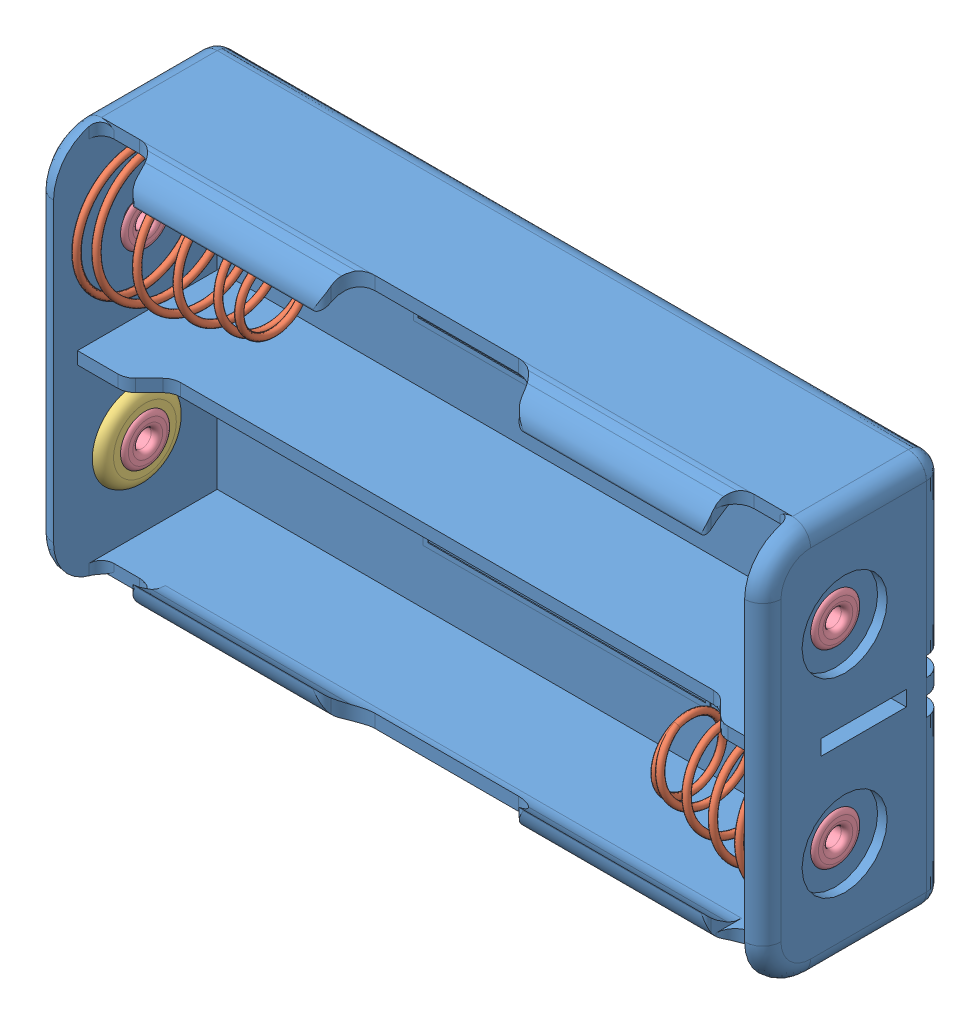
SolidWorks assembly BATTERY HOLDER x2.stp, configuration Default. Lengths in mm.
Overall size (76 41.11 19.41).
9 component instances, 4 part files, 0 mates.
Components (placement in the parent):
- Porta baterias 2x18650.stp-1: Porta baterias 2x18650.stp [Default] at origin size (76 41.11 19)
- Contacto_Helice_v2.0.stp-1: Contacto_Helice_v2.0.stp [Default] at (-35.75 9.925 10.45) x (0 0 -1) z (1 0 0) size (13.74 13.7 14.7)
- Contacto_Helice_v2.0.stp-2: Contacto_Helice_v2.0.stp [Default] at (35.75 -9.925 10.45) x (0 0.924225 0.381849) z (-1 0 0) size (13.74 13.7 14.7)
- Contacto_plano_v1.0.stp-1: Contacto_plano_v1.0.stp [Default] at (36.1 9.925 10.45) x (0 -0.843458 0.537195) z (-1 0 0) size (9 9 1)
- Contacto_plano_v1.0.stp-2: Contacto_plano_v1.0.stp [Default] at (-36.1 -9.925 10.45) x (0 -0.818563 0.574417) z (1 0 0) size (9 9 1)
- remache_v1.0.stp-1: remache_v1.0.stp [Default] at (36.05 9.925 10.45) x (-1 0 0) z (0 -0.633912 0.773406) size (2.5 5.1 5.1)
- remache_v1.0.stp-2: remache_v1.0.stp [Default] at (-36.05 -9.925 10.45) x (-1 0 0) z (0 -0.633912 0.773406) size (2.5 5.1 5.1)
- remache_v1.0.stp-3: remache_v1.0.stp [Default] at (-36.05 9.925 10.45) x (-1 0 0) z (0 -0.633912 0.773406) size (2.5 5.1 5.1)
- remache_v1.0.stp-4: remache_v1.0.stp [Default] at (36.05 -9.925 10.45) x (-1 0 0) z (0 -0.633912 0.773406) size (2.5 5.1 5.1)
